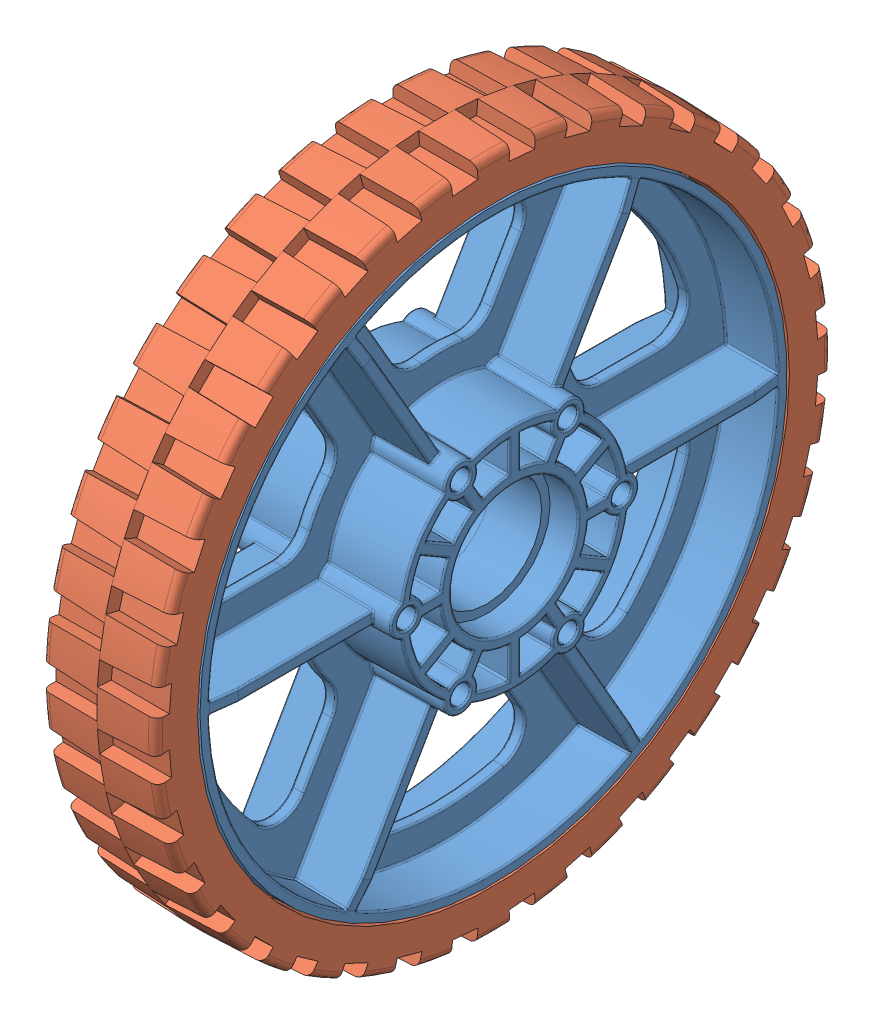
SolidWorks assembly 6in di wheel, configuration Default. Lengths in mm.
Overall size (34.93 152.4 152.4).
2 component instances, 2 part files, 0 mates.
Components (placement in the parent):
- 6 wheel Rev 4-1: 6 wheel Rev 4 [Default] at (-52.6446 9.4231 21.378) size (34.93 132.08 132.08)
- 6 wheel tread II-1: 6 wheel tread II [Default] at (-65.3446 9.4231 21.378) x (0 0 -1) z (1 0 0) size (152.4 152.4 25.58)
